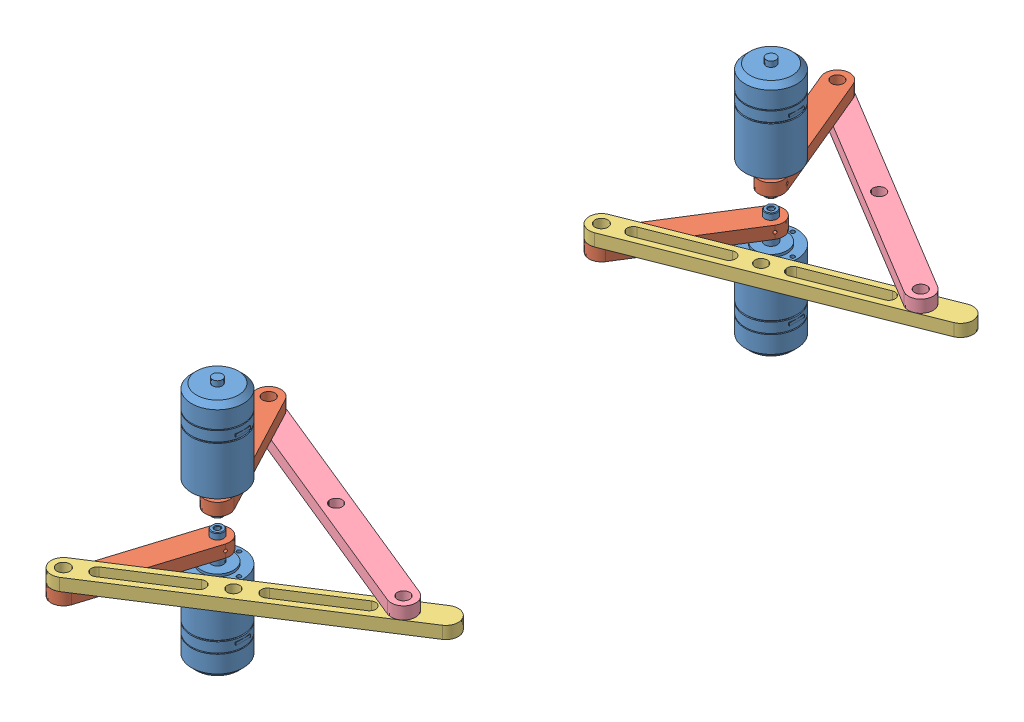
SolidWorks assembly 2, configuration Default. Lengths in mm.
Overall size (240.25 202.8 665.35).
16 component instances, 4 part files, 33 mates.
Components (placement in the parent):
- 3508电机-1: 3508电机 [Default] at (208.6146 288.2751 346.5652) x (0 0 -1) z (1 0 0) size (42 96.4 42)
  - RM3508电机-1: RM3508电机 [默认] at (29.0826 29.1816 80.3714) size (42 96.4 42)
- 3508电机-2: 3508电机 [Default] at (208.6146 288.2751 796.5652) x (0 0 -1) z (1 0 0) size (42 96.4 42)
  - RM3508电机-1: RM3508电机 [默认] at (29.0826 29.1816 80.3714) size (42 96.4 42)
- 10cm-1: 10cm [Default] at (274.1206 377.7567 815.2217) x (-0.297308 0 0.954782) z (0 -1 0) size (120 20 10)
- 20cm-1: 20cm [Default] at (343.3341 387.7567 808.8245) x (0.84079 0 -0.541362) z (0 -1 0) size (245 20 10)
- 10cm-2: 10cm [Default] at (262.3879 377.7567 359.821) x (-0.531962 0 0.846768) z (0 -1 0) size (120 20 10)
- 20cm-2: 20cm [Default] at (328.7728 377.7567 365.3604) x (0.92983 0 -0.36799) z (0 1 0) size (245 20 10)
- 20-1-1: 20-1 [Default] at (427.4131 387.7567 754.6883) x (-0.92577 0 -0.378086) z (0 1 0) size (220 20 10)
- 20-1-2: 20-1 [Default] at (421.7557 397.7567 328.5614) x (-0.855983 0 -0.517005) z (0 -1 0) size (220 20 10)
- 10cm-3: 10cm [Default] at (265.6225 407.7567 723.2769) x (-0.46727 0 -0.884115) z (0 -1 0) size (120 20 10)
- 10cm-4: 10cm [Default] at (269.7726 397.7567 271.3215) x (-0.384268 0 -0.923222) z (0 1 0) size (120 20 10)
- 3508电机-3: 3508电机 [Default] at (208.6146 487.2383 738.4) x (0 0 1) z (1 0 0) size (42 96.4 42)
  - RM3508电机-1: RM3508电机 [默认] at (29.0826 29.1816 80.3714) size (42 96.4 42)
- 3508电机-4: 3508电机 [Default] at (208.6146 487.2383 288.4) x (0 0 1) z (1 0 0) size (42 96.4 42)
  - RM3508电机-1: RM3508电机 [默认] at (29.0826 29.1816 80.3714) size (42 96.4 42)
Mates (geometry in assembly coordinates):
- 同心2: concentric anti-aligned: cylinder of 3508电机-2/RM3508电机-1 through (288.986 382.7567 767.4826) axis (0 -1 0) radius 5; cylinder of 10cm-1 through (288.986 367.7567 767.4826) axis (0 1 0) radius 5
- 距离1: distance = 5 mm aligned: plane of 10cm-1 through (259.2552 377.7567 862.9607) normal (0 1 0); plane of 3508电机-2/RM3508电机-1 through (288.986 382.7567 767.4826) normal (0 1 0)
- 同心5: concentric anti-aligned: cylinder of 10cm-1 through (259.2552 367.7567 862.9607) axis (0 1 0) radius 5; circle of 20cm-1
- 重合6: coincident anti-aligned: plane of 10cm-1 through (259.2552 377.7567 862.9607) normal (0 1 0); plane of 20cm-1 through (448.4328 377.7567 741.1543) normal (0 -1 0)
- 同心6: concentric anti-aligned: cylinder of 3508电机-1/RM3508电机-1 through (288.986 382.7567 317.4826) axis (0 -1 0) radius 5; cylinder of 10cm-2 through (288.986 367.7567 317.4826) axis (0 1 0) radius 5
- 距离2: distance = 5 mm aligned: plane of 10cm-2 through (235.7898 377.7567 402.1594) normal (0 1 0); plane of 3508电机-1/RM3508电机-1 through (288.986 382.7567 317.4826) normal (0 1 0)
- 重合7: coincident anti-aligned: plane of 10cm-2 through (235.7898 377.7567 402.1594) normal (0 1 0); plane of 20cm-2 through (445.0015 377.7567 319.3616) normal (0 -1 0)
- 重合8: coincident anti-aligned: plane of 20cm-2 through (445.0015 387.7567 319.3616) normal (0 1 0); plane of 20-1-2 through (421.7557 387.7567 328.5614) normal (0 -1 0)
- 同心9: concentric anti-aligned: cylinder of 20cm-1 through (427.4131 377.7567 754.6883) axis (0 1 0) radius 5.25; cylinder of 20-1-1 through (427.4131 397.7567 754.6883) axis (0 -1 0) radius 5
- 重合9: coincident anti-aligned: plane of 20cm-1 through (448.4328 387.7567 741.1543) normal (0 1 0); plane of 20-1-1 through (427.4131 387.7567 754.6883) normal (0 -1 0)
- 同心10: concentric anti-aligned: cylinder of 20-1-1 through (242.259 397.7567 679.0711) axis (0 -1 0) radius 5; cylinder of 10cm-3 through (242.259 397.7567 679.0711) axis (0 1 0) radius 5
- 重合10: coincident anti-aligned: plane of 20-1-1 through (427.4131 397.7567 754.6883) normal (0 1 0); plane of 10cm-3 through (242.259 397.7567 679.0711) normal (0 -1 0)
- 同心12: concentric anti-aligned: cylinder of 3508电机-2/RM3508电机-1 through (288.986 382.7567 767.4826) axis (0 -1 0) radius 5; cylinder of 10cm-3 through (288.986 397.7567 767.4826) axis (0 1 0) radius 5
- 同心13: concentric anti-aligned: cylinder of 10cm-2 through (288.986 367.7567 317.4826) axis (0 1 0) radius 10; cylinder of 10cm-4 through (288.986 407.7567 317.4826) axis (0 -1 0) radius 5
- 同心14: concentric aligned: cylinder of 10cm-3 through (288.986 397.7567 767.4826) axis (0 1 0) radius 5; cylinder of 3508电机-3/RM3508电机-1 through (288.986 392.7567 767.4826) axis (0 1 0) radius 5
- 同心15: concentric anti-aligned: cylinder of 10cm-4 through (288.986 407.7567 317.4826) axis (0 -1 0) radius 5; cylinder of 3508电机-4/RM3508电机-1 through (288.986 392.7567 317.4826) axis (0 1 0) radius 5
- 距离4: distance = 5 mm aligned: plane of 3508电机-4/RM3508电机-1 through (288.986 392.7567 317.4826) normal (0 -1 0); plane of 10cm-4 through (250.5592 397.7567 225.1604) normal (0 -1 0)
- 平行1: parallel aligned: plane of ? through (256.9831 358.4567 792.4826) normal (1 0 0); plane of ? through (256.9831 437.0567 792.4826) normal (1 0 0)
- 同心17: concentric aligned: cylinder of ? through (236.9821 348.4567 332.4826) axis (1 0 0) radius 2.55; cylinder of ? through (261.9831 348.4567 332.4826) axis (1 0 0) radius 2.55
- 同心18: concentric aligned: cylinder of ? through (261.9831 427.0567 332.4826) axis (1 0 0) radius 2.55; cylinder of ? through (236.9821 427.0567 332.4826) axis (1 0 0) radius 2.55
- 重合13: coincident anti-aligned: plane of ? through (256.9831 409.0567 342.4826) normal (-1 0 0); plane of ? through (256.9831 437.0567 792.4826) normal (1 0 0)
- 重合14: coincident anti-aligned: plane of ? through (256.9831 358.4567 792.4826) normal (1 0 0); plane of ? through (256.9831 366.4567 292.4826) normal (-1 0 0)
- 同心19: concentric aligned: cylinder of ? through (236.9821 348.4567 302.4826) axis (1 0 0) radius 2.55; cylinder of ? through (261.9831 348.4567 302.4826) axis (1 0 0) radius 2.55
- 同心20: concentric aligned: circle of ?; cylinder of ? through (236.9821 427.0567 302.4826) axis (1 0 0) radius 2.55
- 同心21: concentric anti-aligned: cylinder of ? through (261.9831 427.0567 782.4826) axis (1 0 0) radius 2.55; circle of ?
- 重合15: coincident anti-aligned: plane of ? through (256.9831 409.0567 792.4826) normal (-1 0 0); plane of ? through (256.9831 437.0567 792.4826) normal (1 0 0)
- 重合16: coincident anti-aligned: plane of ? through (256.9831 358.4567 792.4826) normal (1 0 0); plane of ? through (256.9831 366.4567 742.4826) normal (-1 0 0)
- 同心24: concentric aligned: cylinder of ? through (236.9821 348.4567 752.4826) axis (1 0 0) radius 2.55; cylinder of ? through (261.9831 348.4567 752.4826) axis (1 0 0) radius 2.55
- 平行2: parallel aligned: plane of ? through (256.9831 475.0567 792.4826) normal (0 0 1); plane of ? through (246.9831 427.0567 792.4826) normal (0 0 1)
- 平行3: parallel aligned: plane of ? through (246.9831 348.4567 792.4826) normal (0 0 1); plane of ? through (256.9831 366.4567 792.4826) normal (0 0 1)
- 同心26: concentric anti-aligned: circle of 10cm-2; circle of 20cm-2
- 重合19: coincident anti-aligned: circle of 20-1-2; circle of 10cm-4
- 同心27: concentric anti-aligned: circle of 20cm-2; circle of 20-1-2
